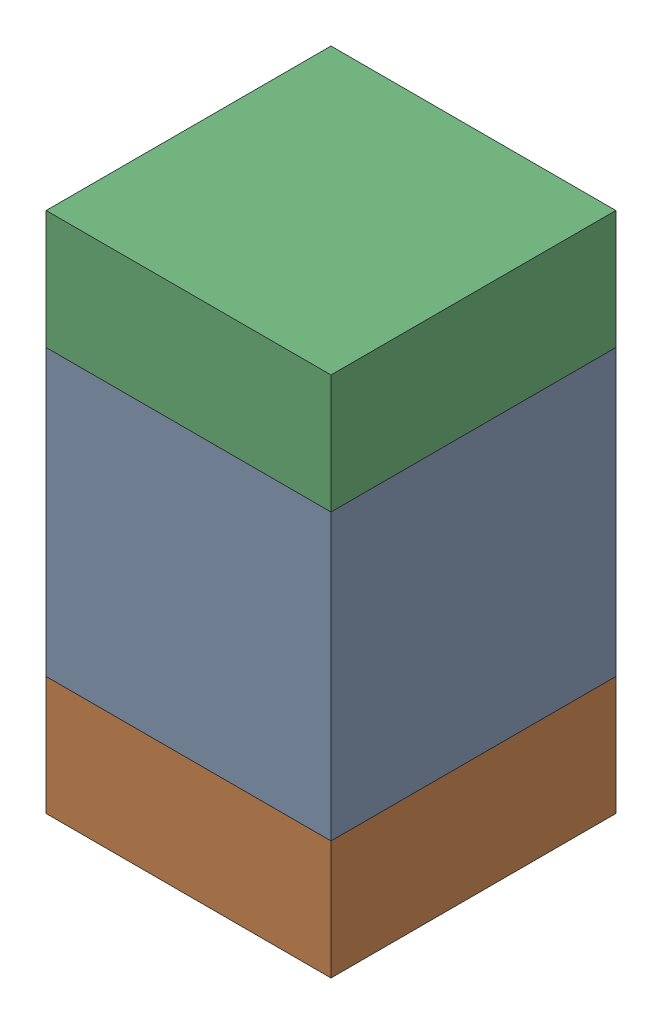
SolidWorks assembly C117_2PCB, configuration Default. Lengths in mm.
Overall size (0.6 1.1 0.6).
6 component instances, 2 part files, 0 mates.
Components (placement in the parent):
- 761606048-1: 761606048 [Default] at (114.7 92 0) size (0.6 0.6 0.6)
  - Extruded_9-1: Extruded_9 [Default] at origin size (0.6 0.6 0.6)
- 854785296-1: 854785296 [Default] at (114.7 91.575 0) size (0.6 0.25 0.6)
  - Extruded_10-1: Extruded_10 [Default] at origin size (0.6 0.25 0.6)
- 854785296-2: 854785296 [Default] at (114.7 92.425 0) size (0.6 0.25 0.6)
  - Extruded_10-1: Extruded_10 [Default] at origin size (0.6 0.25 0.6)
